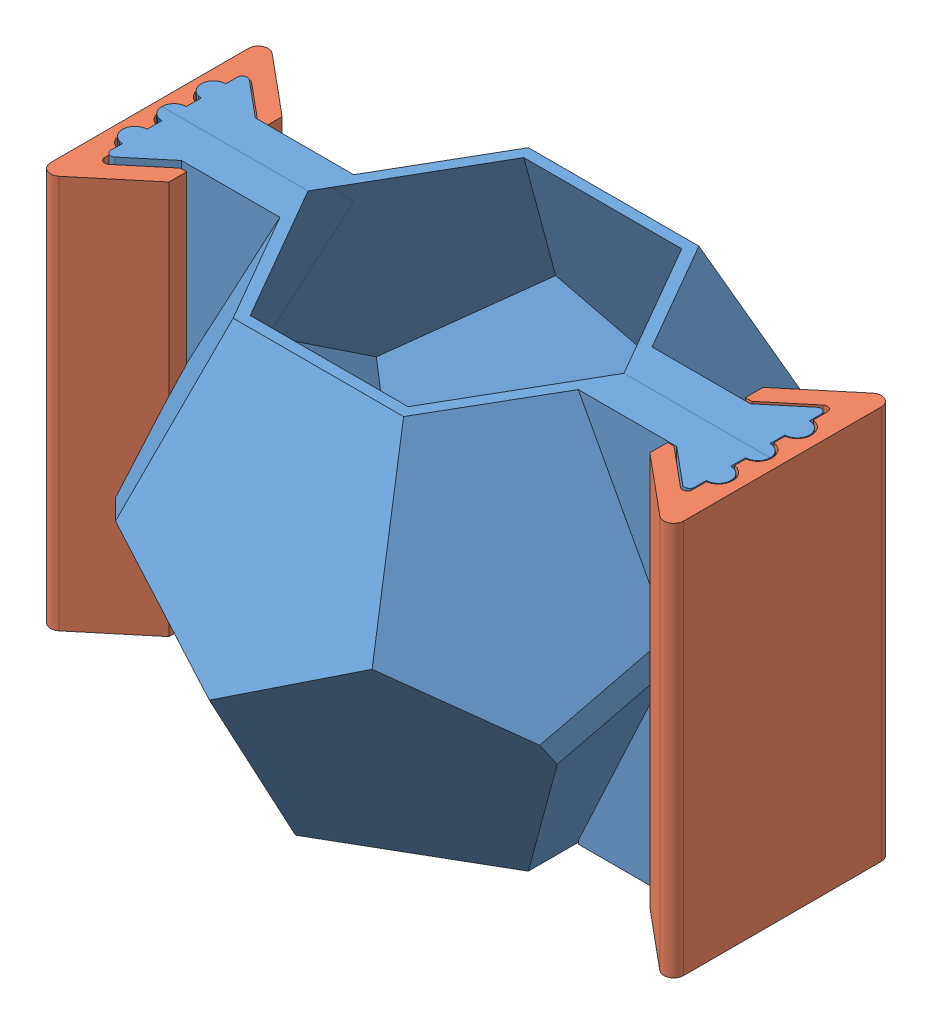
SolidWorks assembly Assembly, configuration Default. Lengths in mm.
Overall size (128.62 81.23 104.29).
3 component instances, 2 part files, 7 mates.
Components (placement in the parent):
- main-1: main [Default] at (23.8187 25.4844 90.7113) size (123.62 80 104.29)
- lock-1: lock [Default] at (54.1296 25.6487 90.7113) size (15.45 80 44.21)
- lock-2: lock [Default] at (-6.4922 104.4179 90.7113) x (-1 0 0) z (0 0 1) size (15.45 80 44.21)
Mates (geometry in assembly coordinates):
- Concentric1: concentric aligned: circle of main-1; circle of lock-1
- Concentric2: concentric aligned: circle of main-1; circle of lock-1
- Concentric3: concentric aligned: circle of main-1; circle of lock-1
- Parallel1: parallel aligned: plane of main-1 through (23.8187 105.4844 90.7113) normal (0 1 0); plane of lock-2 through (-6.4922 104.4179 90.7113) normal (0 1 0)
- Concentric4: concentric aligned: circle of main-1; circle of lock-2
- Concentric5: concentric aligned: circle of main-1; circle of lock-2
- Concentric6: concentric aligned: circle of main-1; circle of lock-2
